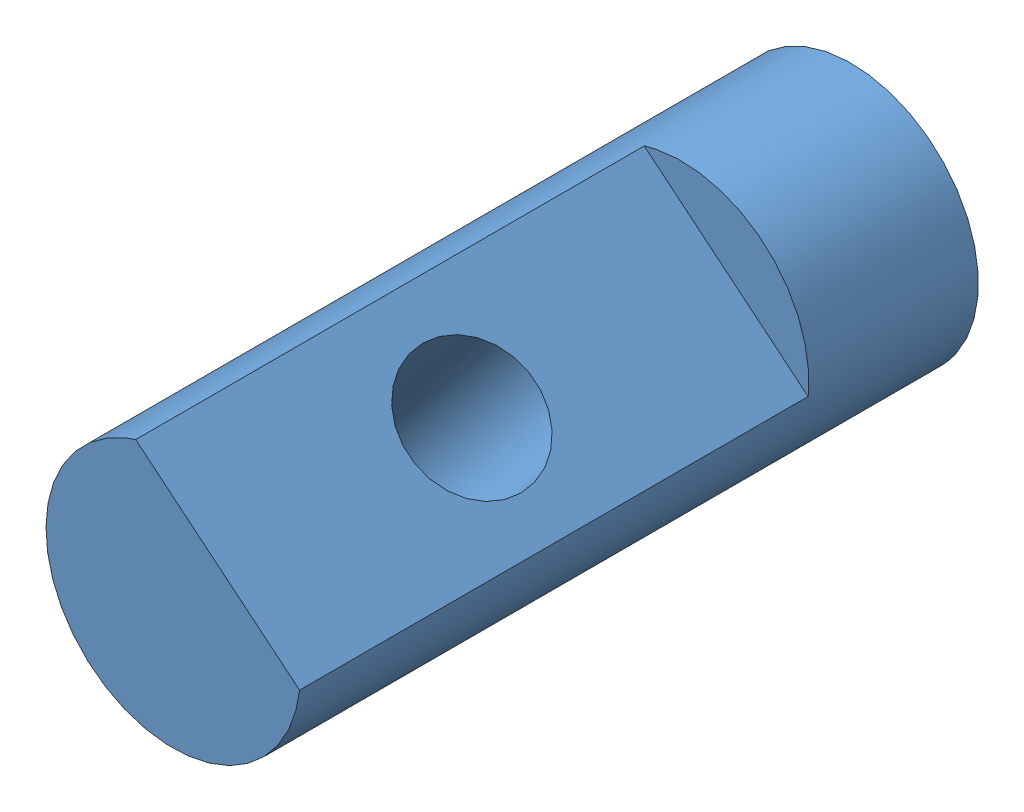
SolidWorks assembly Dc_motorV2, configuration Default. Lengths in mm.
2 component instances, 2 part files, 1 mates.
Components (placement in the parent):
- Motor_bodyV2-2: Motor_bodyV2 [Default] at (34.2418 49.7061 110.5294) size (48.05 48.05 90) (suppressed, hidden)
- Motor_shaftV2-2: Motor_shaftV2 [Default] at (34.2418 49.7061 113.5294) x (0.771631 -0.63607 0) z (0 0 1) size (6 6 16)
Mates (geometry in assembly coordinates):
- Coincident3: coincident aligned: circle of Motor_bodyV2-2; circle of Motor_shaftV2-2
